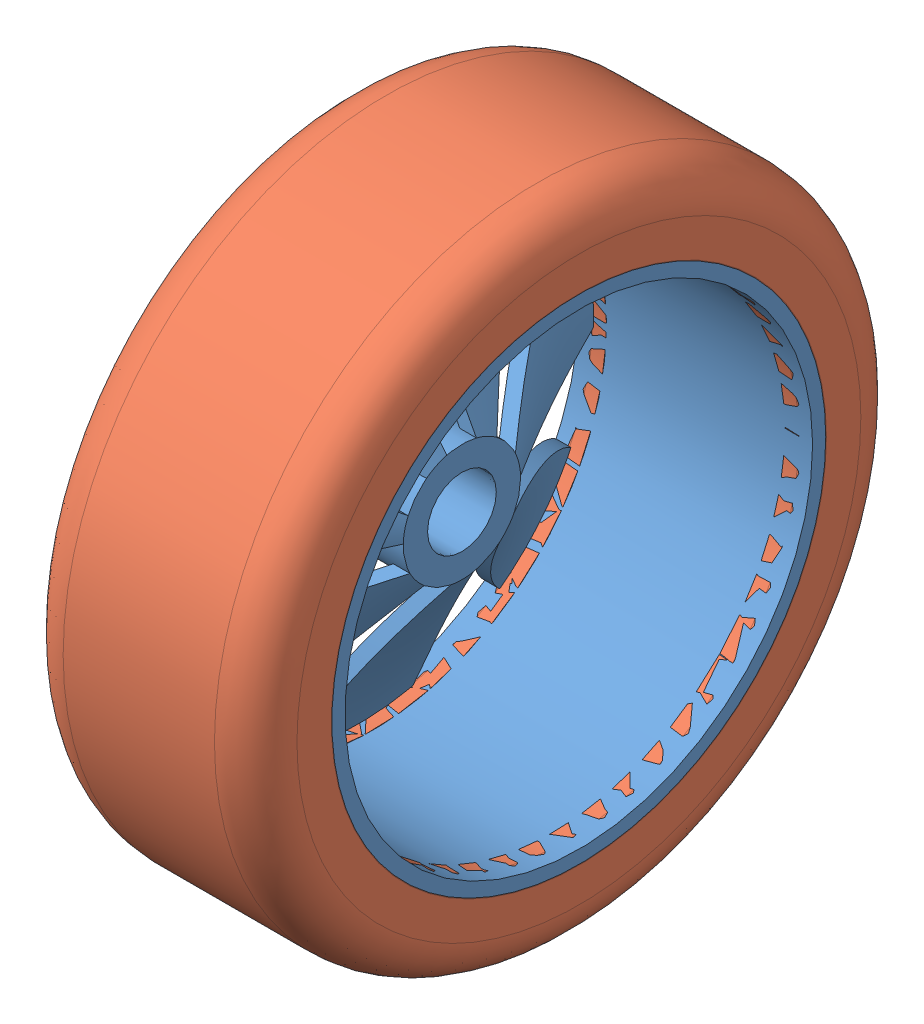
SolidWorks assembly tyre car, configuration Default. Lengths in mm.
Overall size (17.01 47 47).
2 component instances, 2 part files, 1 mates.
Components (placement in the parent):
- rim-1: rim [Default] at (-44.331 10.833 31.2224) x (0 0 -1) z (1 0 0) size (39 39 17)
- rim oart 2-1: rim oart 2 [Default] at (-52.825 10.833 31.2224) size (17 47 47)
Mates (geometry in assembly coordinates):
- Concentric1: concentric anti-aligned: cylinder of rim-1 through (-44.331 10.833 31.2224) axis (1 0 0) radius 19.5; cylinder of rim oart 2-1 through (-35.825 10.833 31.2224) axis (-1 0 0) radius 17
